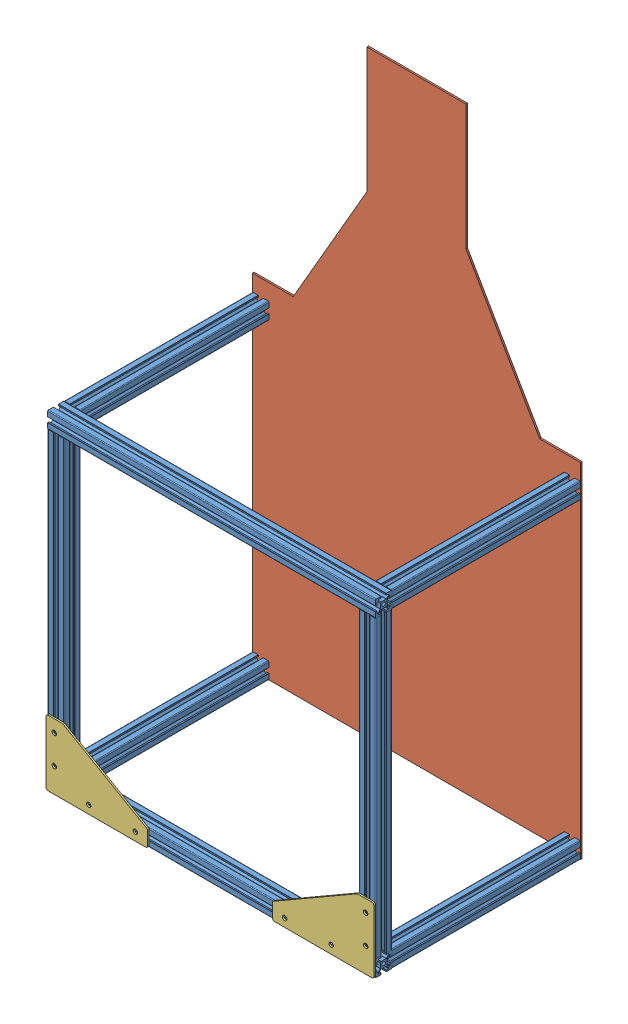
SolidWorks assembly 00 Frame Assembly, configuration Default. Lengths in mm.
Overall size (400 728.86 254).
4 component instances, 3 part files, 12 mates.
Components (placement in the parent):
- 2020-Frame-1: 2020-Frame [Default<As Machined>] at origin size (400 400 250)
- Back Plate-1: Back Plate [Default] at (0 181.4246 -125) size (400 728.86 2)
- Bottom Front Corner Vertice-1: Bottom Front Corner Vertice [Default] at (180 20 127) size (123.92 80 2)
- Bottom Front Corner Vertice-2: Bottom Front Corner Vertice [Default] at (-180 20 125) x (-1 0 0) z (0 0 -1) size (123.92 80 2)
Mates (geometry in assembly coordinates):
- Coincident7: coincident: point of 2020-Frame-1; point of assembly
- Parallel1: parallel aligned: plane of 2020-Frame-1 through (0 0 0) normal (1 0 0); plane of assembly through (0 0 0) normal (1 0 0)
- Parallel2: parallel aligned: plane of 2020-Frame-1 through (0 0 0) normal (0 0 1); plane of assembly through (0 0 0) normal (0 0 1)
- Coincident11: coincident anti-aligned: plane of 2020-Frame-1 through (181 381 -125) normal (0 0 -1); plane of Back Plate-1 through (0 181.4246 -125) normal (0 0 1)
- Coincident12: coincident aligned: plane of Back Plate-1 through (0 181.4246 -125) normal (1 0 0); plane of assembly through (0 0 0) normal (1 0 0)
- Coincident14: coincident anti-aligned: plane of 2020-Frame-1 through (181 19 -125) normal (0 0 -1); plane of Back Plate-1 through (0 181.4246 -125) normal (0 0 1)
- Coincident18: coincident anti-aligned: plane of 2020-Frame-1 through (193.25 400 125) normal (0 0 1); plane of Bottom Front Corner Vertice-1 through (180 20 125) normal (0 0 -1)
- Coincident19: coincident aligned: plane of 2020-Frame-1 through (200 400 118.25) normal (1 0 0); plane of Bottom Front Corner Vertice-1 through (200 80 125) normal (1 0 0)
- Coincident20: coincident aligned: plane of 2020-Frame-1 through (200 0 118.25) normal (0 -1 0); plane of Bottom Front Corner Vertice-1 through (76.077 0 125) normal (0 -1 0)
- Coincident21: coincident anti-aligned: plane of 2020-Frame-1 through (200 13.25 125) normal (0 0 1); plane of Bottom Front Corner Vertice-2 through (-180 20 125) normal (0 0 -1)
- Coincident22: coincident aligned: plane of 2020-Frame-1 through (-200 0 118.25) normal (-1 0 0); plane of Bottom Front Corner Vertice-2 through (-200 80 127) normal (-1 0 0)
- Coincident23: coincident aligned: plane of 2020-Frame-1 through (200 0 118.25) normal (0 -1 0); plane of Bottom Front Corner Vertice-2 through (-76.077 0 127) normal (0 -1 0)
